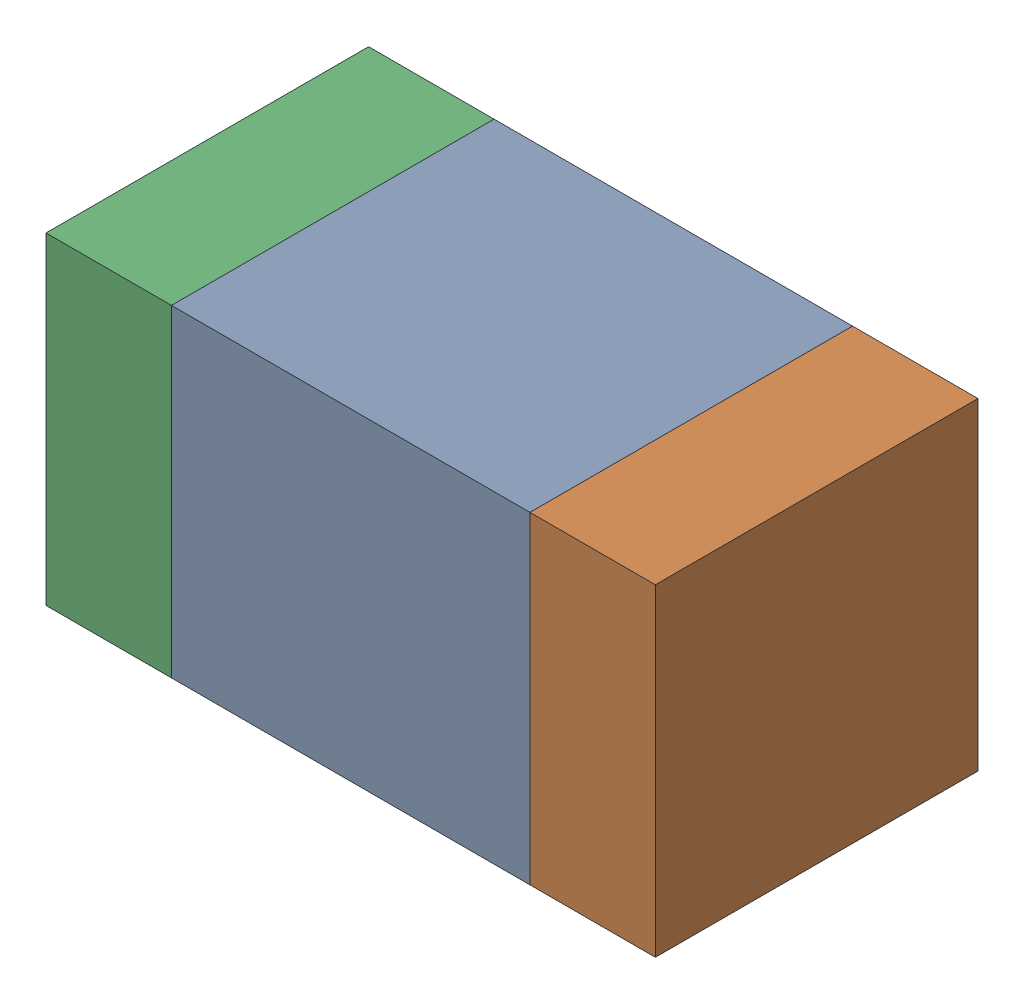
SolidWorks assembly C5, configuration Default. Lengths in mm.
Overall size (1.7 0.9 0.9).
6 component instances, 2 part files, 0 mates.
Components (placement in the parent):
- 5613968128-1: 5613968128 [Default] at (157.225 52 -2.5914) size (1 0.9 0.9)
  - Extruded_4-1: Extruded_4 [Default] at origin size (1 0.9 0.9)
- 5613964048-1: 5613964048 [Default] at (157.9 52 -2.5914) size (0.35 0.9 0.9)
  - Extruded_9-1: Extruded_9 [Default] at origin size (0.35 0.9 0.9)
- 5613964048-2: 5613964048 [Default] at (156.55 52 -2.5914) size (0.35 0.9 0.9)
  - Extruded_9-1: Extruded_9 [Default] at origin size (0.35 0.9 0.9)
